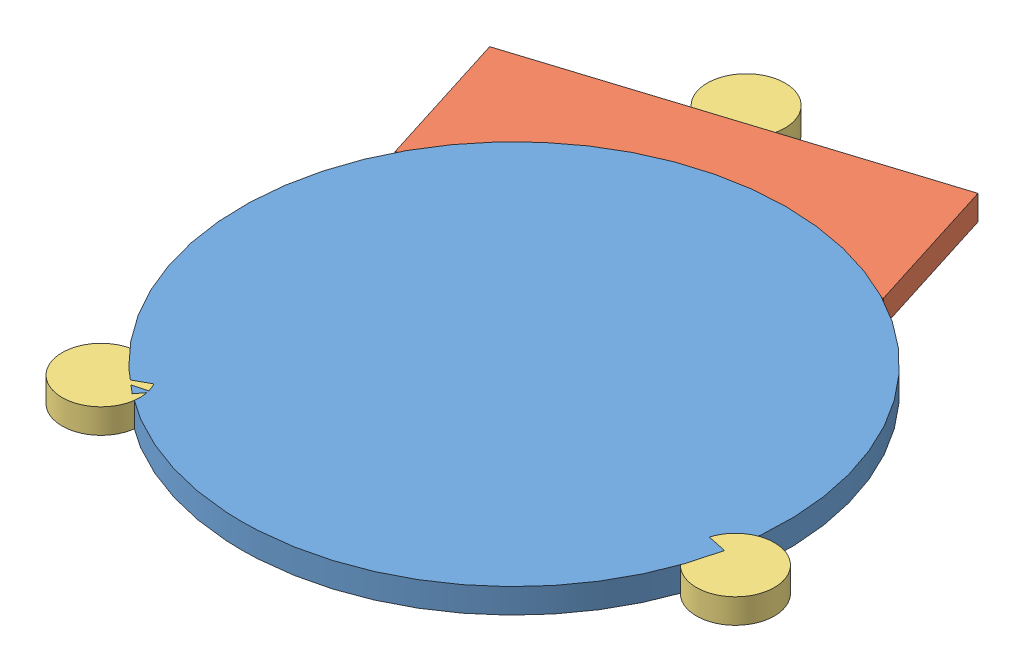
SolidWorks assembly Assem2, configuration Default. Lengths in mm.
Overall size (87.07 6.35 89.74).
5 component instances, 4 part files, 8 mates.
Components (placement in the parent):
- Part3-1: Part3 [Default] at origin size (70 3.17 70)
- Part2-1: Part2 [Default] at (-31.2949 0 -16.0226) x (0.953655 0 -0.300902) z (0.300902 0 0.953655) size (50 3.17 18.6)
- Part4-2: Part4 [Default] at (-25.318 0 27.7354) size (10 3.17 10)
- Part4-3: Part4 [Default] at (36.5607 0 8.1253) size (10 3.17 10)
- Part4-4: Part4 [Default] at (-13.8714 0 -43.6857) size (10 3.17 10)
Mates (geometry in assembly coordinates):
- Coincident1: coincident: line of Part3-1 through (-31.0825 3.175 -16.0896) axis (0.953655 0 -0.300902); line of Part2-1 through (-31.2949 3.175 -16.0226) axis (0.953655 0 -0.300902)
- Coincident2: coincident: plane of Part2-1 through (-31.2949 0 -16.0226) normal (0 -1 0); plane of Part3-1 through (0 0 0) normal (0 -1 0)
- Coincident3: coincident: plane of Part3-1 through (0 3.175 0) normal (0 1 0); plane of Part4-2 through (-25.318 3.175 27.7354) normal (0 1 0)
- Coincident4: coincident: plane of Part3-1 through (0 0 0) normal (0 -1 0); plane of Part4-2 through (-25.318 0 27.7354) normal (0 -1 0)
- Coincident5: coincident: plane of Part3-1 through (0 3.175 0) normal (0 1 0); plane of Part4-3 through (36.5607 3.175 8.1253) normal (0 1 0)
- Coincident6: coincident: plane of Part3-1 through (0 0 0) normal (0 -1 0); plane of Part4-3 through (36.5607 0 8.1253) normal (0 -1 0)
- Coincident7: coincident: plane of Part2-1 through (-31.2949 3.175 -16.0226) normal (0 1 0); plane of Part4-4 through (-13.8714 3.175 -43.6857) normal (0 1 0)
- Coincident8: coincident: plane of Part2-1 through (-31.2949 0 -16.0226) normal (0 -1 0); plane of Part4-4 through (-13.8714 0 -43.6857) normal (0 -1 0)
